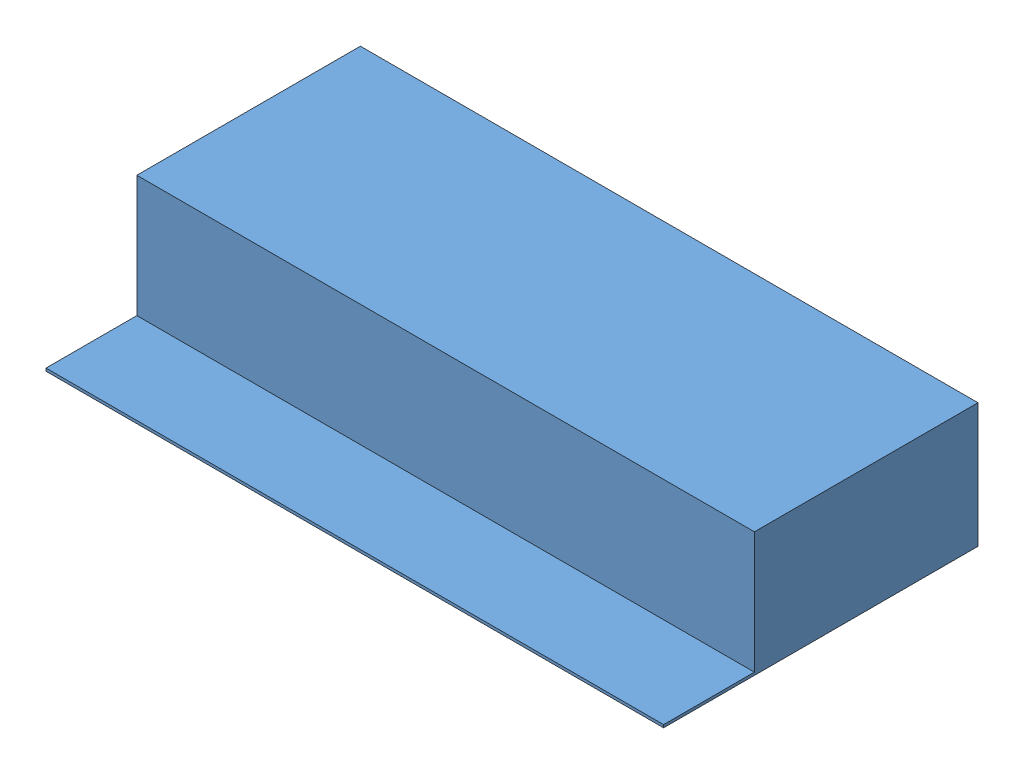
SolidWorks assembly USB-Fronteinbau, configuration Standard. Lengths in mm.
Overall size (221 46.7 112.8).
114 component instances, 17 part files, 9 mates.
Components (placement in the parent):
- Keystone Desktop Patchpanel 12 Port-1: Keystone Desktop Patchpanel 12 Port [Standard] at (72.711 -8.4695 164.75) size (221 46.7 112.5)
- Keystone-USB3-A-1: Keystone-USB3-A [Standard] at (69.5953 10.2683 147.55) size (15.1 18.2 17.8)
  - Keystone-USB-3-Pannel-1: Keystone-USB-3-Pannel [Standard] at (-0.2593 -6.7378 17.2) size (14.6 18.2 2)
  - USB3-A-1: USB3-A [Standard] at (-7.5593 2.2822 29.56) x (0 0 -1) z (0 1 0) size (17.8 15.1 10.24)
    - USB3-A-Pin-4-1: USB3-A-Pin-4 [Standard] at origin size (12.71 1.7 4.79)
    - USB3-A-Pin-8-1: USB3-A-Pin-8 [Standard] at origin size (16.44 1.6 5.89)
    - USB3-A-Pin-5-1: USB3-A-Pin-5 [Standard] at origin size (16.44 2.05 5.89)
    - USB3-A-Pin-3-1: USB3-A-Pin-3 [Standard] at origin size (12.71 1.7 4.79)
    - USB3-A-Pin-9-1: USB3-A-Pin-9 [Standard] at origin size (16.44 2.05 5.89)
    - USB3-A-Pin-6-1: USB3-A-Pin-6 [Standard] at origin size (16.44 1.6 5.89)
    - USB3-A-Pin-7-1: USB3-A-Pin-7 [Standard] at origin size (16.44 1.6 5.89)
    - USB3-A-Inner-Plastic-1: USB3-A-Inner-Plastic [Standard] at origin size (16 13.1 7.94)
    - USB3-A-Pin-1-1: USB3-A-Pin-1 [Standard] at origin size (12.71 1.7 4.79)
    - USB3-A-Outer-Shell-1: USB3-A-Outer-Shell [Standard] at origin size (16.66 15.1 10.24)
    - USB3-A-Pin-2-1: USB3-A-Pin-2 [Standard] at origin size (12.71 1.7 4.79)
- Keystone-USB3-A-8: Keystone-USB3-A [Standard] at (51.4453 10.2683 147.55) size (15.1 18.2 17.8)
  - Keystone-USB-3-Pannel-1: Keystone-USB-3-Pannel [Standard] at (-0.2593 -6.7378 17.2) size (14.6 18.2 2)
  - USB3-A-1: USB3-A [Standard] at (-7.5593 2.2822 29.56) x (0 0 -1) z (0 1 0) size (17.8 15.1 10.24)
    - USB3-A-Pin-4-1: USB3-A-Pin-4 [Standard] at origin size (12.71 1.7 4.79)
    - USB3-A-Pin-8-1: USB3-A-Pin-8 [Standard] at origin size (16.44 1.6 5.89)
    - USB3-A-Pin-5-1: USB3-A-Pin-5 [Standard] at origin size (16.44 2.05 5.89)
    - USB3-A-Pin-3-1: USB3-A-Pin-3 [Standard] at origin size (12.71 1.7 4.79)
    - USB3-A-Pin-9-1: USB3-A-Pin-9 [Standard] at origin size (16.44 2.05 5.89)
    - USB3-A-Pin-6-1: USB3-A-Pin-6 [Standard] at origin size (16.44 1.6 5.89)
    - USB3-A-Pin-7-1: USB3-A-Pin-7 [Standard] at origin size (16.44 1.6 5.89)
    - USB3-A-Inner-Plastic-1: USB3-A-Inner-Plastic [Standard] at origin size (16 13.1 7.94)
    - USB3-A-Pin-1-1: USB3-A-Pin-1 [Standard] at origin size (12.71 1.7 4.79)
    - USB3-A-Outer-Shell-1: USB3-A-Outer-Shell [Standard] at origin size (16.66 15.1 10.24)
    - USB3-A-Pin-2-1: USB3-A-Pin-2 [Standard] at origin size (12.71 1.7 4.79)
- Keystone-USB3-A-9: Keystone-USB3-A [Standard] at (33.2953 10.2683 147.55) size (15.1 18.2 17.8)
  - Keystone-USB-3-Pannel-1: Keystone-USB-3-Pannel [Standard] at (-0.2593 -6.7378 17.2) size (14.6 18.2 2)
  - USB3-A-1: USB3-A [Standard] at (-7.5593 2.2822 29.56) x (0 0 -1) z (0 1 0) size (17.8 15.1 10.24)
    - USB3-A-Pin-4-1: USB3-A-Pin-4 [Standard] at origin size (12.71 1.7 4.79)
    - USB3-A-Pin-8-1: USB3-A-Pin-8 [Standard] at origin size (16.44 1.6 5.89)
    - USB3-A-Pin-5-1: USB3-A-Pin-5 [Standard] at origin size (16.44 2.05 5.89)
    - USB3-A-Pin-3-1: USB3-A-Pin-3 [Standard] at origin size (12.71 1.7 4.79)
    - USB3-A-Pin-9-1: USB3-A-Pin-9 [Standard] at origin size (16.44 2.05 5.89)
    - USB3-A-Pin-6-1: USB3-A-Pin-6 [Standard] at origin size (16.44 1.6 5.89)
    - USB3-A-Pin-7-1: USB3-A-Pin-7 [Standard] at origin size (16.44 1.6 5.89)
    - USB3-A-Inner-Plastic-1: USB3-A-Inner-Plastic [Standard] at origin size (16 13.1 7.94)
    - USB3-A-Pin-1-1: USB3-A-Pin-1 [Standard] at origin size (12.71 1.7 4.79)
    - USB3-A-Outer-Shell-1: USB3-A-Outer-Shell [Standard] at origin size (16.66 15.1 10.24)
    - USB3-A-Pin-2-1: USB3-A-Pin-2 [Standard] at origin size (12.71 1.7 4.79)
- Keystone-USB3-A-10: Keystone-USB3-A [Standard] at (15.1453 10.2683 147.55) size (15.1 18.2 17.8)
  - Keystone-USB-3-Pannel-1: Keystone-USB-3-Pannel [Standard] at (-0.2593 -6.7378 17.2) size (14.6 18.2 2)
  - USB3-A-1: USB3-A [Standard] at (-7.5593 2.2822 29.56) x (0 0 -1) z (0 1 0) size (17.8 15.1 10.24)
    - USB3-A-Pin-4-1: USB3-A-Pin-4 [Standard] at origin size (12.71 1.7 4.79)
    - USB3-A-Pin-8-1: USB3-A-Pin-8 [Standard] at origin size (16.44 1.6 5.89)
    - USB3-A-Pin-5-1: USB3-A-Pin-5 [Standard] at origin size (16.44 2.05 5.89)
    - USB3-A-Pin-3-1: USB3-A-Pin-3 [Standard] at origin size (12.71 1.7 4.79)
    - USB3-A-Pin-9-1: USB3-A-Pin-9 [Standard] at origin size (16.44 2.05 5.89)
    - USB3-A-Pin-6-1: USB3-A-Pin-6 [Standard] at origin size (16.44 1.6 5.89)
    - USB3-A-Pin-7-1: USB3-A-Pin-7 [Standard] at origin size (16.44 1.6 5.89)
    - USB3-A-Inner-Plastic-1: USB3-A-Inner-Plastic [Standard] at origin size (16 13.1 7.94)
    - USB3-A-Pin-1-1: USB3-A-Pin-1 [Standard] at origin size (12.71 1.7 4.79)
    - USB3-A-Outer-Shell-1: USB3-A-Outer-Shell [Standard] at origin size (16.66 15.1 10.24)
    - USB3-A-Pin-2-1: USB3-A-Pin-2 [Standard] at origin size (12.71 1.7 4.79)
- Keystone-USB3-A-11: Keystone-USB3-A [Standard] at (-3.0047 10.2683 147.55) size (15.1 18.2 17.8)
  - Keystone-USB-3-Pannel-1: Keystone-USB-3-Pannel [Standard] at (-0.2593 -6.7378 17.2) size (14.6 18.2 2)
  - USB3-A-1: USB3-A [Standard] at (-7.5593 2.2822 29.56) x (0 0 -1) z (0 1 0) size (17.8 15.1 10.24)
    - USB3-A-Pin-4-1: USB3-A-Pin-4 [Standard] at origin size (12.71 1.7 4.79)
    - USB3-A-Pin-8-1: USB3-A-Pin-8 [Standard] at origin size (16.44 1.6 5.89)
    - USB3-A-Pin-5-1: USB3-A-Pin-5 [Standard] at origin size (16.44 2.05 5.89)
    - USB3-A-Pin-3-1: USB3-A-Pin-3 [Standard] at origin size (12.71 1.7 4.79)
    - USB3-A-Pin-9-1: USB3-A-Pin-9 [Standard] at origin size (16.44 2.05 5.89)
    - USB3-A-Pin-6-1: USB3-A-Pin-6 [Standard] at origin size (16.44 1.6 5.89)
    - USB3-A-Pin-7-1: USB3-A-Pin-7 [Standard] at origin size (16.44 1.6 5.89)
    - USB3-A-Inner-Plastic-1: USB3-A-Inner-Plastic [Standard] at origin size (16 13.1 7.94)
    - USB3-A-Pin-1-1: USB3-A-Pin-1 [Standard] at origin size (12.71 1.7 4.79)
    - USB3-A-Outer-Shell-1: USB3-A-Outer-Shell [Standard] at origin size (16.66 15.1 10.24)
    - USB3-A-Pin-2-1: USB3-A-Pin-2 [Standard] at origin size (12.71 1.7 4.79)
- Keystone-USB3-A-12: Keystone-USB3-A [Standard] at (-21.1547 10.2683 147.55) size (15.1 18.2 17.8)
  - Keystone-USB-3-Pannel-1: Keystone-USB-3-Pannel [Standard] at (-0.2593 -6.7378 17.2) size (14.6 18.2 2)
  - USB3-A-1: USB3-A [Standard] at (-7.5593 2.2822 29.56) x (0 0 -1) z (0 1 0) size (17.8 15.1 10.24)
    - USB3-A-Pin-4-1: USB3-A-Pin-4 [Standard] at origin size (12.71 1.7 4.79)
    - USB3-A-Pin-8-1: USB3-A-Pin-8 [Standard] at origin size (16.44 1.6 5.89)
    - USB3-A-Pin-5-1: USB3-A-Pin-5 [Standard] at origin size (16.44 2.05 5.89)
    - USB3-A-Pin-3-1: USB3-A-Pin-3 [Standard] at origin size (12.71 1.7 4.79)
    - USB3-A-Pin-9-1: USB3-A-Pin-9 [Standard] at origin size (16.44 2.05 5.89)
    - USB3-A-Pin-6-1: USB3-A-Pin-6 [Standard] at origin size (16.44 1.6 5.89)
    - USB3-A-Pin-7-1: USB3-A-Pin-7 [Standard] at origin size (16.44 1.6 5.89)
    - USB3-A-Inner-Plastic-1: USB3-A-Inner-Plastic [Standard] at origin size (16 13.1 7.94)
    - USB3-A-Pin-1-1: USB3-A-Pin-1 [Standard] at origin size (12.71 1.7 4.79)
    - USB3-A-Outer-Shell-1: USB3-A-Outer-Shell [Standard] at origin size (16.66 15.1 10.24)
    - USB3-A-Pin-2-1: USB3-A-Pin-2 [Standard] at origin size (12.71 1.7 4.79)
- Keystone-USB3-A-13: Keystone-USB3-A [Standard] at (-39.3047 10.2683 147.55) size (15.1 18.2 17.8)
  - Keystone-USB-3-Pannel-1: Keystone-USB-3-Pannel [Standard] at (-0.2593 -6.7378 17.2) size (14.6 18.2 2)
  - USB3-A-1: USB3-A [Standard] at (-7.5593 2.2822 29.56) x (0 0 -1) z (0 1 0) size (17.8 15.1 10.24)
    - USB3-A-Pin-4-1: USB3-A-Pin-4 [Standard] at origin size (12.71 1.7 4.79)
    - USB3-A-Pin-8-1: USB3-A-Pin-8 [Standard] at origin size (16.44 1.6 5.89)
    - USB3-A-Pin-5-1: USB3-A-Pin-5 [Standard] at origin size (16.44 2.05 5.89)
    - USB3-A-Pin-3-1: USB3-A-Pin-3 [Standard] at origin size (12.71 1.7 4.79)
    - USB3-A-Pin-9-1: USB3-A-Pin-9 [Standard] at origin size (16.44 2.05 5.89)
    - USB3-A-Pin-6-1: USB3-A-Pin-6 [Standard] at origin size (16.44 1.6 5.89)
    - USB3-A-Pin-7-1: USB3-A-Pin-7 [Standard] at origin size (16.44 1.6 5.89)
    - USB3-A-Inner-Plastic-1: USB3-A-Inner-Plastic [Standard] at origin size (16 13.1 7.94)
    - USB3-A-Pin-1-1: USB3-A-Pin-1 [Standard] at origin size (12.71 1.7 4.79)
    - USB3-A-Outer-Shell-1: USB3-A-Outer-Shell [Standard] at origin size (16.66 15.1 10.24)
    - USB3-A-Pin-2-1: USB3-A-Pin-2 [Standard] at origin size (12.71 1.7 4.79)
- Keystone-USB-C-1: Keystone-USB-C [Standard] at (-59.2745 8.3193 147.55) size (14.6 18.2 8.17)
  - Keystone-USB-C-Pannel-1: Keystone-USB-C-Pannel [Standard] at (1.5605 -4.7888 17.2) size (14.6 18.2 2)
  - USB-C-1: USB-C [Standard] at (-5.7395 3.3112 21.9) x (-1 0 0) z (0 0 -1) size (8.94 3.77 8.17)
- Keystone-USB2-A-1: Keystone-USB2-A [Standard] at (-90.464 20.7305 164.75) x (-1 0 0) z (0 0 -1) size (15.8 18.2 18.93)
  - Keystone-USB-2-Pannel-1: Keystone-USB-2-Pannel [Standard] at (-14.6 -17.2 0) x (-1 0 0) z (0 0 -1) size (14.6 18.2 2)
  - 96939-1: 96939 [Standard] at (-7.3 -9.1 0.3) size (15.8 7.12 18.93)
- Keystone-USB2-A-2: Keystone-USB2-A [Standard] at (-108.614 20.7305 164.75) x (-1 0 0) z (0 0 -1) size (15.8 18.2 18.93)
  - Keystone-USB-2-Pannel-1: Keystone-USB-2-Pannel [Standard] at (-14.6 -17.2 0) x (-1 0 0) z (0 0 -1) size (14.6 18.2 2)
  - 96939-1: 96939 [Standard] at (-7.3 -9.1 0.3) size (15.8 7.12 18.93)
- Keystone-USB2-A-3: Keystone-USB2-A [Standard] at (-126.764 20.7305 164.75) x (-1 0 0) z (0 0 -1) size (15.8 18.2 18.93)
  - Keystone-USB-2-Pannel-1: Keystone-USB-2-Pannel [Standard] at (-14.6 -17.2 0) x (-1 0 0) z (0 0 -1) size (14.6 18.2 2)
  - 96939-1: 96939 [Standard] at (-7.3 -9.1 0.3) size (15.8 7.12 18.93)
- Keystone-USB2-A-4: Keystone-USB2-A [Standard] at (-144.914 20.7305 164.75) x (-1 0 0) z (0 0 -1) size (15.8 18.2 18.93)
  - Keystone-USB-2-Pannel-1: Keystone-USB-2-Pannel [Standard] at (-14.6 -17.2 0) x (-1 0 0) z (0 0 -1) size (14.6 18.2 2)
  - 96939-1: 96939 [Standard] at (-7.3 -9.1 0.3) size (15.8 7.12 18.93)
Mates (geometry in assembly coordinates):
- Deckungsgleich1: coincident anti-aligned: plane of Keystone Desktop Patchpanel 12 Port-1 through (54.736 19.7305 165.75) normal (0 -1 0); plane of Keystone-USB3-A-1/Keystone-USB-3-Pannel-1 through (69.336 19.7305 165.75) normal (0 1 0)
- Deckungsgleich2: coincident aligned: plane of Keystone Desktop Patchpanel 12 Port-1 through (72.711 -8.4695 164.75) normal (0 0 -1); plane of Keystone-USB3-A-1/Keystone-USB-3-Pannel-1 through (69.336 3.5305 164.75) normal (0 0 -1)
- Deckungsgleich3: coincident anti-aligned: plane of Keystone Desktop Patchpanel 12 Port-1 through (54.736 19.7305 165.75) normal (1 0 0); plane of Keystone-USB3-A-1/Keystone-USB-3-Pannel-1 through (54.736 3.5305 165.75) normal (-1 0 0)
- Deckungsgleich4: coincident aligned: plane of Keystone Desktop Patchpanel 12 Port-1 through (72.711 -8.4695 164.75) normal (0 0 -1); plane of Keystone-USB-C-1/Keystone-USB-C-Pannel-1 through (-57.714 3.5305 164.75) normal (0 0 -1)
- Deckungsgleich5: coincident anti-aligned: plane of Keystone Desktop Patchpanel 12 Port-1 through (-72.314 19.7305 165.75) normal (1 0 0); plane of Keystone-USB-C-1/Keystone-USB-C-Pannel-1 through (-72.314 3.5305 165.75) normal (-1 0 0)
- Deckungsgleich6: coincident anti-aligned: plane of Keystone Desktop Patchpanel 12 Port-1 through (-72.314 19.7305 165.75) normal (0 -1 0); plane of Keystone-USB-C-1/Keystone-USB-C-Pannel-1 through (-57.714 19.7305 165.75) normal (0 1 0)
- Deckungsgleich7: coincident aligned: plane of Keystone Desktop Patchpanel 12 Port-1 through (72.711 -8.4695 164.75) normal (0 0 -1); plane of Keystone-USB2-A-1/Keystone-USB-2-Pannel-1 through (-75.864 3.5305 164.75) normal (0 0 -1)
- Deckungsgleich8: coincident anti-aligned: plane of Keystone Desktop Patchpanel 12 Port-1 through (-90.464 19.7305 165.75) normal (1 0 0); plane of Keystone-USB2-A-1/Keystone-USB-2-Pannel-1 through (-90.464 3.5305 165.75) normal (-1 0 0)
- Deckungsgleich9: coincident anti-aligned: plane of Keystone Desktop Patchpanel 12 Port-1 through (-90.464 19.7305 165.75) normal (0 -1 0); plane of Keystone-USB2-A-1/Keystone-USB-2-Pannel-1 through (-75.864 19.7305 165.75) normal (0 1 0)
